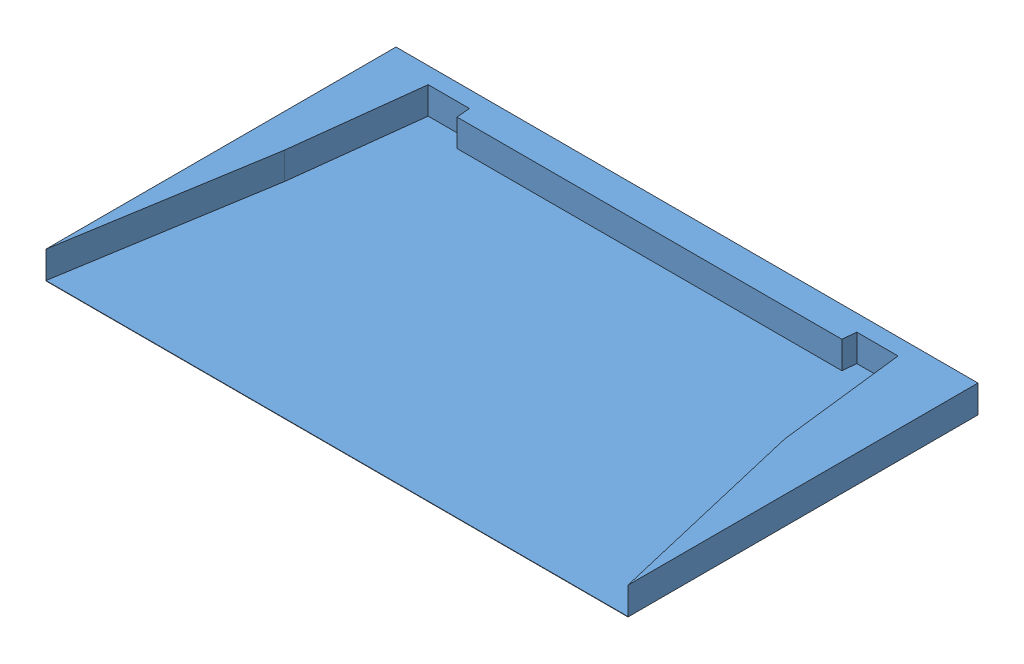
SolidWorks assembly Assieme1, configuration Default. Lengths in mm.
Overall size (1495.04 71 899.08).
27 component instances, 12 part files, 5 mates.
Components (placement in the parent):
- Gabbia legna_2-1: Gabbia legna_2 [Default] at origin size (1277 1003.06 855) (hidden)
  - Base-1: Base [Default] at origin size (1277 275 855)
  - Piede gabbia-1: Piede gabbia [Default] at (603.5 -100 412.5) size (100 100 220)
  - Piede gabbia-3: Piede gabbia [Default] at (-603.5 -100 -412.5) x (-1 0 0) z (0 0 -1) size (100 100 220)
  - Piede gabbia 2-1: Piede gabbia 2 [Default] at (-598.5 -100 407.5) size (110 100 230)
  - Piede gabbia 2-2: Piede gabbia 2 [Default] at (598.5 -100 -407.5) x (-1 0 0) z (0 0 -1) size (110 100 230)
  - Parte laterale-1: Parte laterale [Default] at (615.4552 860.0464 0) x (0 0 -1) z (0.999991 0.004229 0) size (835 773 100)
  - Parte posteriore-1: Parte posteriore [Default] at (0 115 -405) x (-1 0 0) z (0 0 -1) size (1100 760 25)
  - Assieme porta anteriore-1: Assieme porta anteriore [Default] at (25 495 415) size (1100 760 32.5)
    - Parte anteriore-1: Parte anteriore [Default] at (-25 -380 -10) size (1100 760 32.5)
    - Porta parte anteriore-3: Porta parte anteriore [Default] at (-25 0 -10) size (1080 380 32.5)
    - Fermo porta parte anteriore-1: Fermo porta parte anteriore [Default] at (-561.5 276 -5.5) size (64 45 10)
    - Fermo porta parte anteriore-2: Fermo porta parte anteriore [Default] at (511.5 276 -5.5) x (-1 0 0) z (0 0 -1) size (64 45 10)
  - Parte laterale-2: Parte laterale [Default] at (-614.3712 860.0598 0) x (0 0 1) z (-0.999984 0.005734 0) size (835 773 100)
  - Fermo laterale-1: Fermo laterale [Default] at (620.5813 704.9949 390) x (0.707107 0.707107 0) z (0 0 1) size (50 108.59 15)
  - Fermo laterale-2: Fermo laterale [Default] at (620.5813 704.9949 -405) x (0.707107 0.707107 0) z (0 0 1) size (50 108.59 15)
  - Fermo laterale-5: Fermo laterale [Default] at (-619.7168 705.6802 405) x (-0.677793 0.735252 0) z (0 0 -1) size (50 108.59 15)
  - Fermo laterale-6: Fermo laterale [Default] at (-619.7168 705.6802 -390) x (-0.677793 0.735252 0) z (0 0 -1) size (50 108.59 15)
  - hex bolt gradeab_iso-2: hex bolt gradeab_iso [ISO 4014 - M10 x 90 x 26-N] at (603.6108 704.9949 411.4) x (0 0 -1) z (1 0 0) size (96.4 18.48 16)
  - hex bolt gradeab_iso-3: hex bolt gradeab_iso [ISO 4014 - M10 x 90 x 26-N] at (603.6108 704.9949 -411.4) x (0 0 1) z (-1 0 0) size (96.4 18.48 16)
  - hex bolt gradeab_iso-4: hex bolt gradeab_iso [ISO 4014 - M10 x 90 x 26-N] at (-602.7602 704.9907 -411.4) x (0 0 1) z (-1 0 0) size (96.4 18.48 16)
  - hex bolt gradeab_iso-5: hex bolt gradeab_iso [ISO 4014 - M10 x 90 x 26-N] at (-602.7602 704.9907 411.4) x (0 0 -1) z (1 0 0) size (96.4 18.48 16)
  - hex nut gradec_iso-2: hex nut gradec_iso [ISO - 4034 - M10 - N] at (-602.7602 704.9907 320.5) x (0.923728 0.383049 0) z (0 0 -1) size (16 18.48 9.5)
  - hex nut gradec_iso-3: hex nut gradec_iso [ISO - 4034 - M10 - N] at (-602.7602 704.9907 -320.5) size (16 18.48 9.5)
  - hex nut gradec_iso-4: hex nut gradec_iso [ISO - 4034 - M10 - N] at (603.6108 704.9949 -320.5) size (16 18.48 9.5)
  - hex nut gradec_iso-5: hex nut gradec_iso [ISO - 4034 - M10 - N] at (603.6108 704.9949 320.5) x (0.923728 0.383049 0) z (0 0 -1) size (16 18.48 9.5)
- Parte1^Assieme1-1: Parte1^Assieme1 [Default] at (-603.5 -100 -412.5) x (1 0 0) z (0 -1 0) size (1495.04 899.08 71) (virtual)
Mates (geometry in assembly coordinates):
- SulPosto1: in place: plane of ? through (-641.7442 -450.3096 864.5) normal (0 -1 0); plane of ? through (0 -450.3096 0) normal (0 -1 0); moOrthogonalPlaneRef_w of ? through (-641.7442 -450.3096 864.5) normal (0 -1 0); plane of ? through (0 -450.3096 0) normal (0 0 -1); plane of ? through (-641.7442 -450.3096 864.5) normal (0 -1 0); plane of ? through (0 -450.3096 0) normal (-1 0 0); plane of Gabbia legna_2-1/Piede gabbia-3 through (-603.5 -100 -412.5) normal (0 -1 0); unknown of Parte1^Assieme1-1
- Coincidente1: coincident aligned: plane of Gabbia legna_2-1/Piede gabbia-3; plane of Parte1^Assieme1-1
- Coincidente2: coincident aligned: moOrthogonalPlaneRef_w of Gabbia legna_2-1/Piede gabbia-3 through (-603.5 -100 -412.5) normal (0 0 1); plane of Parte1^Assieme1-1 through (-603.5 -100 -412.5) normal (0 0 1)
- Coincidente3: coincident anti-aligned: moOrthogonalPlaneRef_w of Gabbia legna_2-1/Piede gabbia-3 through (-603.5 -100 -412.5) normal (-1 0 0); plane of Parte1^Assieme1-1 through (-603.5 -100 -412.5) normal (1 0 0)
- Coincidente6: coordinate: point of Gabbia legna_2-1
